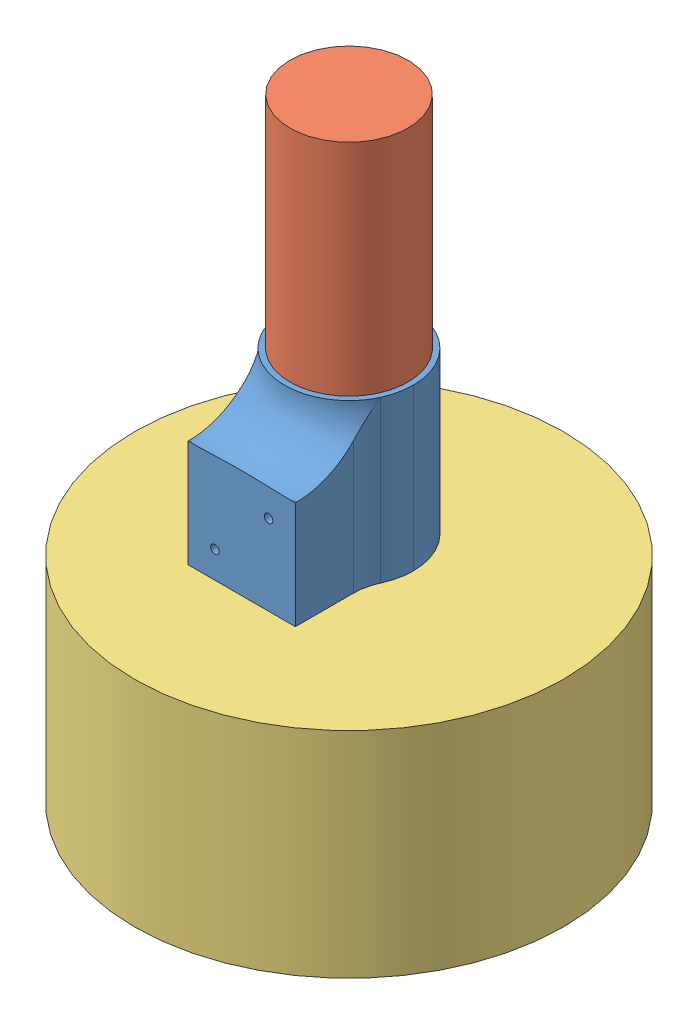
SolidWorks assembly 电机装配, configuration 默认. Lengths in mm.
Overall size (80 114.5 80).
3 component instances, 3 part files, 4 mates.
Components (placement in the parent):
- 电机固定套筒-1: 电机固定套筒 [默认] at (4.3516 -15.7004 35.2099) size (40.42 30.1 34.42)
- 电机-1: 电机 [默认] at (4.3516 55.2996 35.2099) x (0.429023 0 -0.903294) z (-0.903294 0 -0.429023) size (22 91 22)
- 简易版轮子-1: 简易版轮子 [默认] at (4.3516 -59.2004 35.2099) size (80 40 80)
Mates (geometry in assembly coordinates):
- 同心1: concentric anti-aligned: cylinder of 电机固定套筒-1 through (4.3516 -11.7004 35.2099) axis (0 1 0) radius 11; cylinder of 电机-1 through (4.3516 55.2996 35.2099) axis (0 -1 0) radius 11
- 重合1: coincident anti-aligned: plane of 电机固定套筒-1 through (-17.6484 -11.7004 57.2099) normal (0 1 0); plane of 电机-1 through (-0.8653 -11.7004 20.5544) normal (0 -1 0)
- 同心2: concentric anti-aligned: cylinder of 电机-1 through (4.3516 -15.7004 35.2099) axis (0 -1 0) radius 2; cylinder of 简易版轮子-1 through (4.3516 -115.7004 35.2099) axis (0 1 0) radius 2.5
- 重合2: coincident anti-aligned: plane of 电机-1 through (3.9847 -19.2004 33.2438) normal (0 -1 0); plane of 简易版轮子-1 through (4.3516 -35.7004 35.2099) normal (0 1 0)
